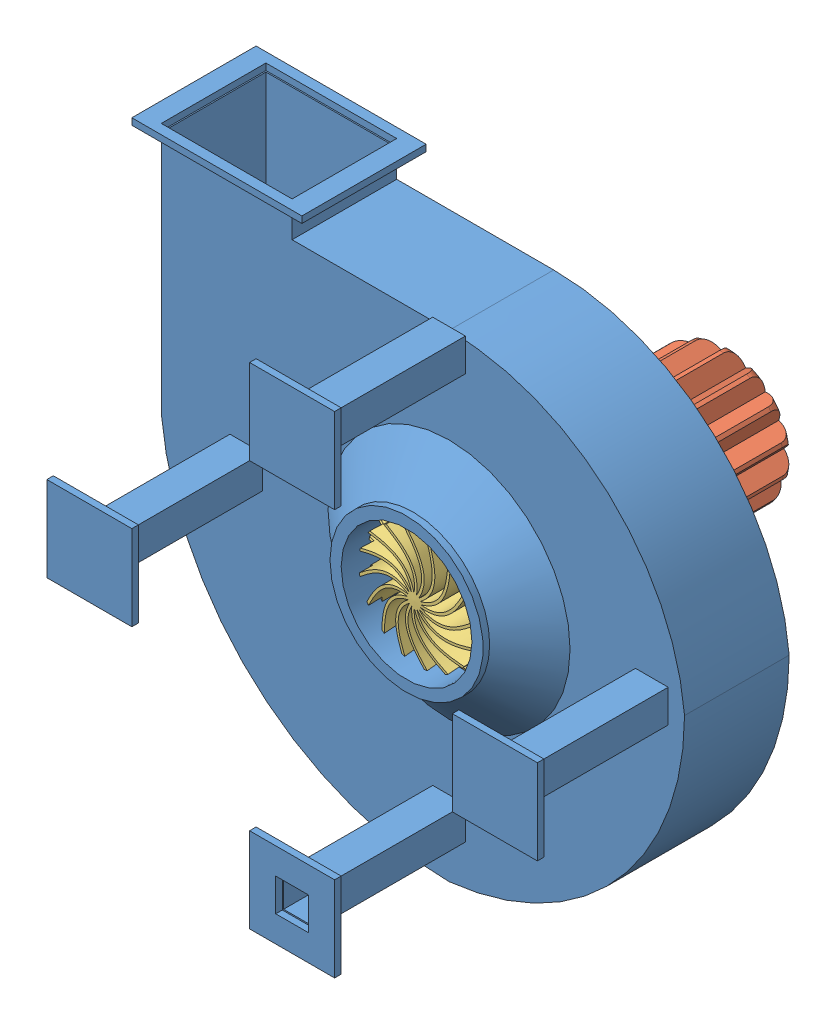
SolidWorks assembly Centrifugal Pump Assembly, configuration Default. Lengths in mm.
Overall size (845 784 670.35).
3 component instances, 3 part files, 4 mates.
Components (placement in the parent):
- Centrifugal Pump-1: Centrifugal Pump [Default] at (186.0108 748.9336 -335.1444) size (845 784 415)
- Motor for Pump-1: Motor for Pump [Default] at (448.6341 648.8338 -603.1444) x (-0.894995 0.446076 0) z (0 0 1) size (260 260 300.35)
- Impeller-1: Impeller [Default] at (448.6341 648.8338 -310.1444) x (-0.826457 0.562999 0) z (0 0 1) size (398.27 398.27 194.27)
Mates (geometry in assembly coordinates):
- Concentric1: concentric aligned: cylinder of Centrifugal Pump-1 through (448.6341 648.8338 -218.1444) axis (0 0 -1) radius 10; cylinder of Motor for Pump-1 through (448.6341 648.8338 -305.1444) axis (0 0 -1) radius 9
- Coincident1: coincident anti-aligned: plane of Centrifugal Pump-1 through (447.4139 690.8338 -335.1444) normal (0 0 -1); plane of Motor for Pump-1 through (448.6341 648.8338 -335.1444) normal (0 0 1)
- Concentric2: concentric aligned: cylinder of Motor for Pump-1 through (448.6341 648.8338 -305.1444) axis (0 0 -1) radius 9; cylinder of Impeller-1 through (448.6341 648.8338 -305.1444) axis (0 0 -1) radius 10
- Coincident2: coincident: plane of Motor for Pump-1 through (448.6341 648.8338 -305.1444) normal (0 0 1); plane of Impeller-1 through (448.6341 648.8338 -305.1444) normal (0 0 -1)
